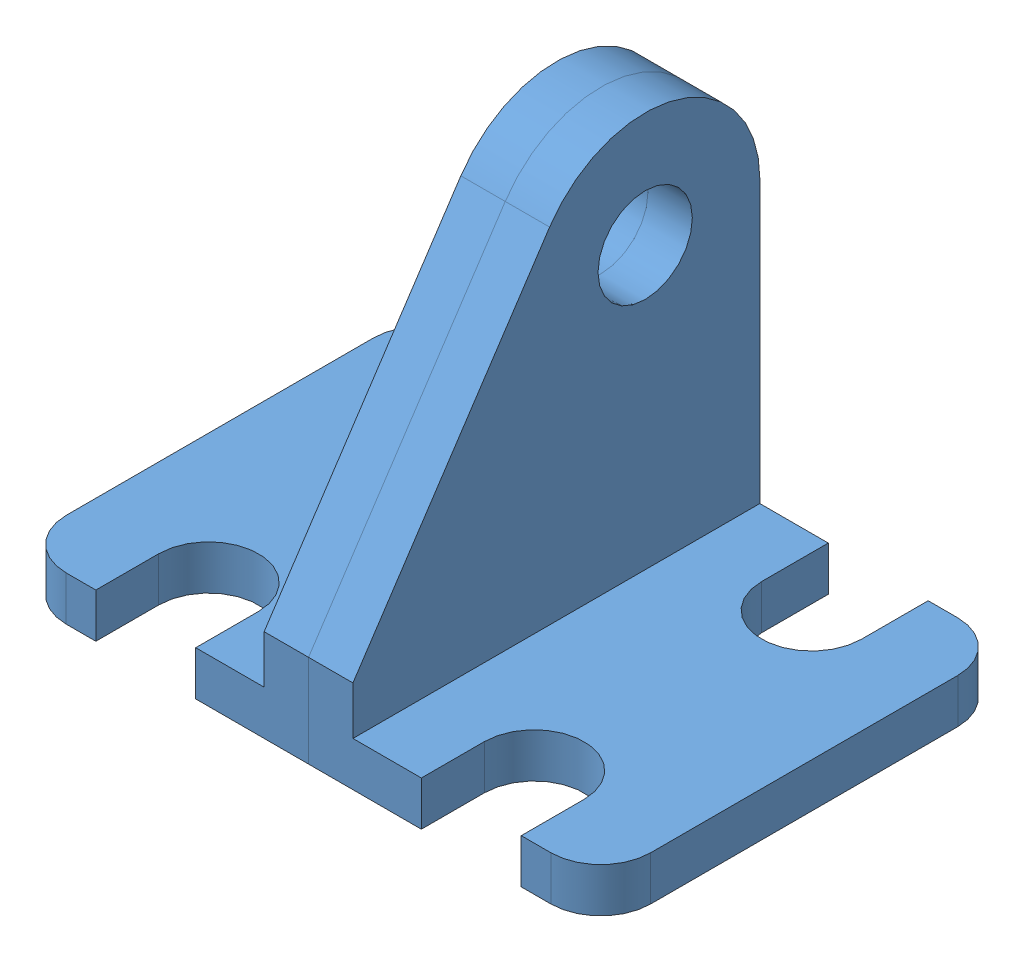
SolidWorks assembly Gimbal Side Bracket (NCM-PC075), configuration NCM-PC075. Lengths in mm.
Overall size (40.13 30.23 27.94).
2 component instances, 1 part files, 6 mates.
Components (placement in the parent):
- NCM-PC075_NCMP-C-Bracket-1: NCM-PC075_NCMP-C-Bracket [075F] at origin size (20.07 30.23 27.94)
- NCM-PC075_NCMP-C-Bracket-2: NCM-PC075_NCMP-C-Bracket [075R] x (-1 0 0) z (0 0 -1) size (20.07 30.23 27.94)
Mates (geometry in assembly coordinates):
- Coincident1: coincident aligned: plane of NCM-PC075_NCMP-C-Bracket-1 through (0 0 0) normal (0 1 0); plane of assembly through (0 0 0) normal (0 1 0)
- Coincident2: coincident aligned: plane of NCM-PC075_NCMP-C-Bracket-1 through (0 0 0) normal (0 1 0); plane of NCM-PC075_NCMP-C-Bracket-2
- Coincident3: coincident aligned: plane of NCM-PC075_NCMP-C-Bracket-1 through (0 0 0) normal (0 0 1); plane of assembly through (0 0 0) normal (0 0 1)
- Coincident4: coincident anti-aligned: plane of NCM-PC075_NCMP-C-Bracket-1 through (0 0 0) normal (0 0 1); plane of NCM-PC075_NCMP-C-Bracket-2 through (0 0 0) normal (0 0 -1)
- Symmetric1: symmetric aligned: plane of NCM-PC075_NCMP-C-Bracket-1 through (0 0 0) normal (1 0 0); plane of NCM-PC075_NCMP-C-Bracket-2 through (0 0 0) normal (-1 0 0); plane of assembly through (0 0 0) normal (1 0 0)
- Coincident5: coincident anti-aligned: plane of NCM-PC075_NCMP-C-Bracket-1 through (0 3.048 13.97) normal (-1 0 0); plane of NCM-PC075_NCMP-C-Bracket-2 through (0 3.048 -13.97) normal (1 0 0)
